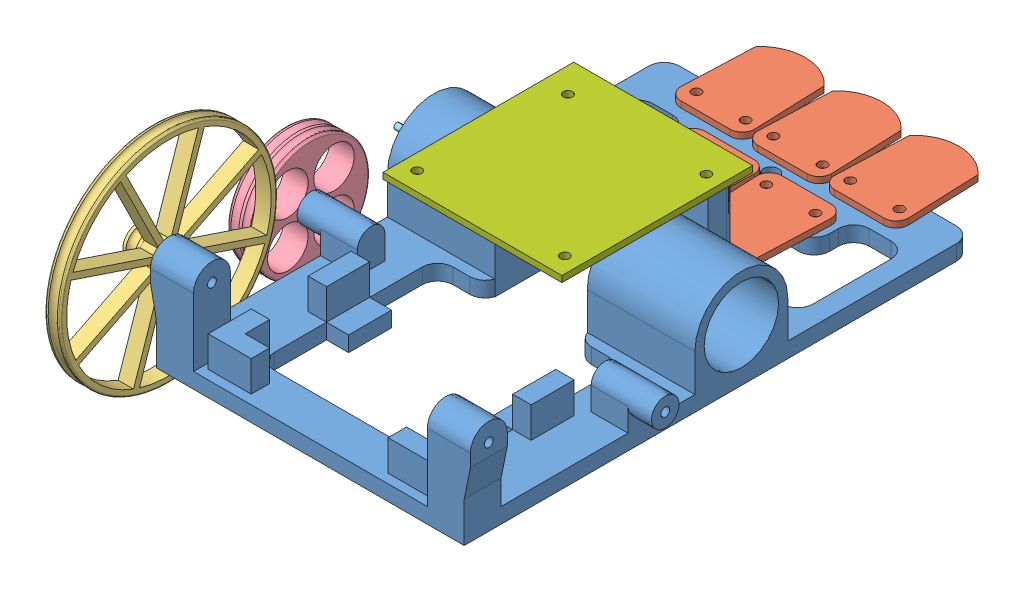
SolidWorks assembly LFR3, configuration Default. Lengths in mm.
Overall size (123.2 89.25 224.46).
11 component instances, 7 part files, 25 mates.
Components (placement in the parent):
- BODY5-1: BODY5 [Default] at origin size (115.2 33 165)
- SENSOR-1: SENSOR [Default] at (12.5 5 -44.78) size (24 2 32.42)
- SENSOR-2: SENSOR [Default] at (-12.5 5 -44.78) size (24 2 32.42)
- SENSOR-3: SENSOR [Default] at (25 5 -57.42) x (-1 0 0) z (0 0 -1) size (24 2 32.42)
- SENSOR-4: SENSOR [Default] at (0 5 -57.42) x (-1 0 0) z (0 0 -1) size (24 2 32.42)
- SENSOR-5: SENSOR [Default] at (-25 5 -57.42) x (-1 0 0) z (0 0 -1) size (24 2 32.42)
- INTERMEDIATE65mm-2: INTERMEDIATE65mm [Default] at (-52 27 94) x (0 0.948191 -0.317701) z (-1 0 0) size (70.5 70.5 10)
- WHEEL-2: WHEEL [Default] at (-65.6 12.5 42.2315) x (0 -0.70765 -0.706563) z (1 0 0) size (38 38 8)
- MM28Motor-1: MM28Motor [Default] at (-50 17.1 9.9) x (0 0.924225 0.381849) z (-1 0 0) size (24.2 24.2 44.5)
- MOTOR_PULLEY-1: MOTOR_PULLEY [Default] at (-51.6 17.1 9.9) x (0 -0.231551 0.972823) z (-1 0 0) size (10 10 5)
- MAIN-1: MAIN [Default] at (-5.005 32.2 11.3) size (58.17 2 62)
Mates (geometry in assembly coordinates):
- Coincident2: coincident anti-aligned: plane of BODY5-1 through (0 5 0) normal (0 1 0); plane of SENSOR-4 through (8 5 -57.42) normal (0 -1 0)
- Coincident3: coincident anti-aligned: plane of BODY5-1 through (0 5 0) normal (0 1 0); plane of SENSOR-5 through (-17 5 -57.42) normal (0 -1 0)
- Coincident4: coincident anti-aligned: plane of BODY5-1 through (0 5 0) normal (0 1 0); plane of SENSOR-1 through (4.5 5 -44.78) normal (0 -1 0)
- Coincident5: coincident anti-aligned: plane of BODY5-1 through (0 5 0) normal (0 1 0); plane of SENSOR-2 through (-20.5 5 -44.78) normal (0 -1 0)
- Coincident6: coincident anti-aligned: plane of BODY5-1 through (0 5 0) normal (0 1 0); plane of SENSOR-3 through (33 5 -57.42) normal (0 -1 0)
- Concentric1: concentric anti-aligned: cylinder of BODY5-1 through (-8 -0.001 -58.5) axis (0 1 0) radius 1.5; cylinder of SENSOR-4 through (-8 7 -58.5) axis (0 -1 0) radius 1.5
- Coincident7: coincident aligned: cylinder of BODY5-1 through (8 -0.001 -58.5) axis (0 1 0) radius 1.5; circle of SENSOR-4
- Concentric2: concentric anti-aligned: cylinder of BODY5-1 through (-20.5 -5 -43.7) axis (0 1 0) radius 1.5; cylinder of SENSOR-2 through (-20.5 7 -43.7) axis (0 -1 0) radius 1.5
- Concentric3: concentric anti-aligned: cylinder of BODY5-1 through (-4.5 -5 -43.7) axis (0 1 0) radius 1.5; cylinder of SENSOR-2 through (-4.5 7 -43.7) axis (0 -1 0) radius 1.5
- Concentric4: concentric anti-aligned: cylinder of BODY5-1 through (4.5 -5 -43.7) axis (0 1 0) radius 1.5; cylinder of SENSOR-1 through (4.5 7 -43.7) axis (0 -1 0) radius 1.5
- Concentric5: concentric anti-aligned: cylinder of BODY5-1 through (20.5 -5 -43.7) axis (0 1 0) radius 1.5; cylinder of SENSOR-1 through (20.5 7 -43.7) axis (0 -1 0) radius 1.5
- Concentric7: concentric anti-aligned: cylinder of BODY5-1 through (33 -0.001 -58.5) axis (0 1 0) radius 1.5; cylinder of SENSOR-3 through (33 7 -58.5) axis (0 -1 0) radius 1.5
- Concentric8: concentric anti-aligned: cylinder of BODY5-1 through (17 -0.001 -58.5) axis (0 1 0) radius 1.5; cylinder of SENSOR-3 through (17 7 -58.5) axis (0 -1 0) radius 1.5
- Concentric9: concentric anti-aligned: cylinder of BODY5-1 through (-33 -0.001 -58.5) axis (0 1 0) radius 1.5; cylinder of SENSOR-5 through (-33 7 -58.5) axis (0 -1 0) radius 1.5
- Concentric10: concentric anti-aligned: cylinder of BODY5-1 through (-17 -0.001 -58.5) axis (0 1 0) radius 1.5; cylinder of SENSOR-5 through (-17 7 -58.5) axis (0 -1 0) radius 1.5
- Concentric11: concentric aligned: cylinder of BODY5-1 through (-19.5 17.1 9.9) axis (-1 0 0) radius 12.1; cylinder of MM28Motor-1 through (-19.5 17.1 9.9) axis (-1 0 0) radius 12.1
- Coincident8: coincident anti-aligned: plane of BODY5-1 through (-19.5 0 0) normal (-1 0 0); plane of MM28Motor-1 through (-19.5 17.1 9.9) normal (1 0 0)
- Concentric12: concentric anti-aligned: line of MM28Motor-1 through (-62 17.1 9.9) axis (1 0 0); axis of MOTOR_PULLEY-1 through (-51.6 17.1 9.9) axis (-1 0 0)
- Coincident9: coincident anti-aligned: plane of MM28Motor-1 through (-51.6 17.1 9.9) normal (-1 0 0); plane of MOTOR_PULLEY-1 through (-51.6 17.1 9.9) normal (1 0 0)
- Concentric13: concentric anti-aligned: cylinder of BODY5-1 through (-39 12.5 42.2315) axis (-1 0 0) radius 1.45; cylinder of WHEEL-2 through (-65.6 12.5 42.2315) axis (1 0 0) radius 1.55
- Coincident10: coincident anti-aligned: plane of BODY5-1 through (-57.6 12.5 42.2315) normal (-1 0 0); plane of WHEEL-2 through (-57.6 12.5 42.2315) normal (1 0 0)
- Coincident11: coincident anti-aligned: plane of BODY5-1 through (-52 27 94) normal (-1 0 0); plane of INTERMEDIATE65mm-2 through (-52 15.801 60.5763) normal (1 0 0)
- Concentric14: concentric anti-aligned: cylinder of BODY5-1 through (-38 27 94) axis (-1 0 0) radius 1.45; cylinder of INTERMEDIATE65mm-2 through (-62 27 94) axis (1 0 0) radius 1.55
- Concentric15: concentric: cylinder of BODY5-1 through (19 32.2 -9.7) axis (0 -1 0) radius 1.5; cylinder of MAIN-1 through (19 34.2 -9.7) axis (0 -1 0) radius 1.5
- Coincident12: coincident anti-aligned: plane of BODY5-1 through (0 32.2 0) normal (0 1 0); plane of MAIN-1 through (-5.005 32.2 11.3) normal (0 -1 0)
